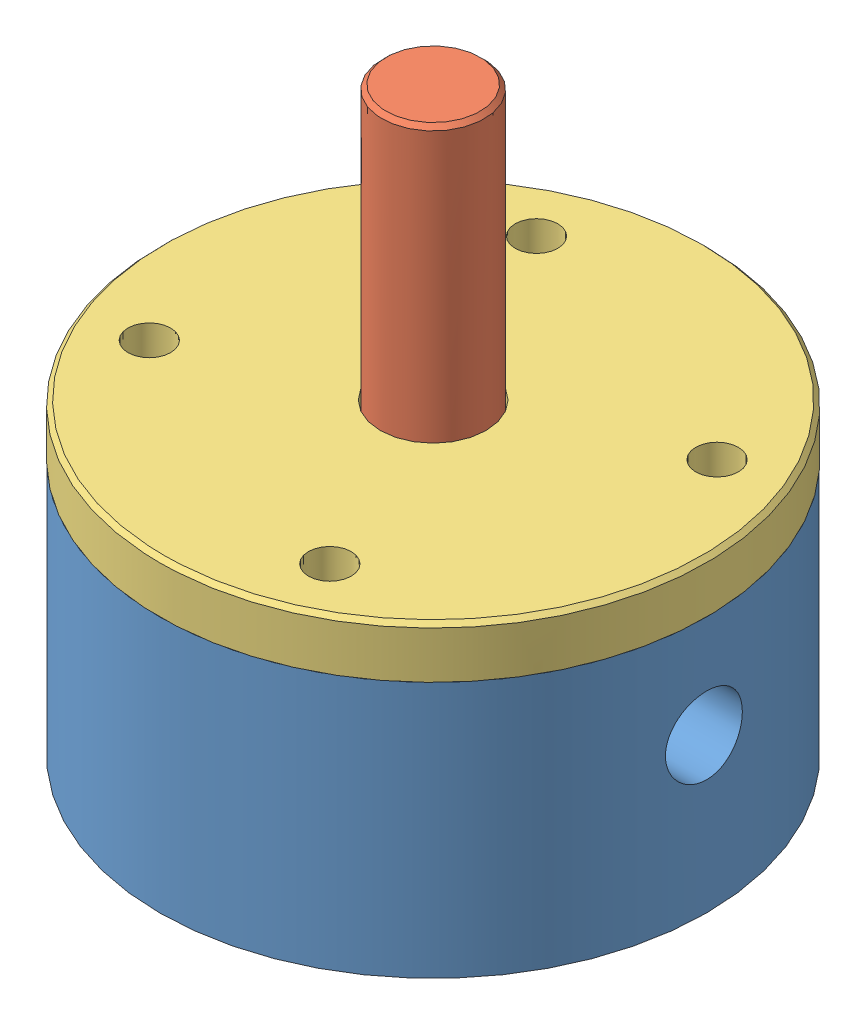
SolidWorks assembly Montagem_Shutter_v10, configuration Default. Lengths in mm.
Overall size (32 34.5 32).
3 component instances, 3 part files, 6 mates.
Components (placement in the parent):
- Sede_Inferior_v10-1: Sede_Inferior_v10 [Valor predeterminado<Como usinado>] at origin size (32 15 32)
- Desviador_v10-1: Desviador_v10 [Valor predeterminado] x (-0.941666 0 -0.336549) z (0.336549 0 -0.941666) size (18 34.5 18)
- Sede_superior_v9-1: Sede_superior_v9 [Valor predeterminado] at (0 7.5 0) size (32 4 32)
Mates (geometry in assembly coordinates):
- Coincident1: coordinate: point of Sede_Inferior_v10-1; point of assembly
- Concentric1: concentric aligned: cylinder of Sede_Inferior_v10-1 through (0 -9 0) axis (0 -1 0) radius 3; cylinder of Desviador_v10-1 through (0 0 0) axis (0 -1 0) radius 3
- Coincident2: coincident anti-aligned: plane of Sede_Inferior_v10-1 through (9 -5 0) normal (0 1 0); plane of Desviador_v10-1 through (-2.825 -5 -1.0096) normal (0 -1 0)
- Concêntrico1: concentric aligned: cylinder of Desviador_v10-1 through (0 0 0) axis (0 -1 0) radius 3; cylinder of Sede_superior_v9-1 through (0 7.5 0) axis (0 -1 0) radius 3.1
- Coincidente3: coincident anti-aligned: plane of Sede_superior_v9-1 through (9 6 0) normal (0 -1 0); plane of Sede_Inferior_v10-1 through (0 6 0) normal (0 1 0)
- Concêntrico4: concentric aligned: cylinder of Sede_Inferior_v10-1 through (5.2827 6 11.3288) axis (0 1 0) radius 1.25; cylinder of Sede_superior_v9-1 through (5.2827 9 11.3288) axis (0 1 0) radius 1.25
